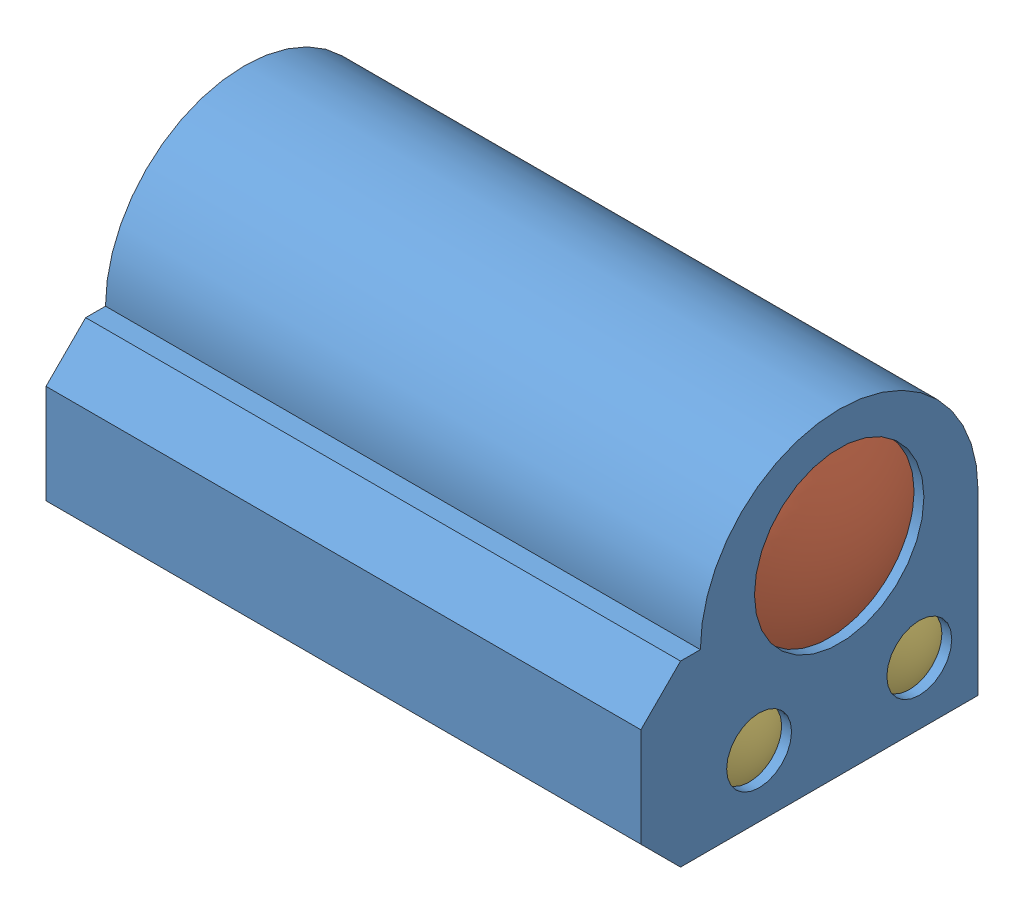
SolidWorks assembly Assem1, configuration Default. Lengths in mm.
Overall size (152.5 80 85).
4 component instances, 3 part files, 6 mates.
Components (placement in the parent):
- cam-1: cam [Default] at (69.598 59.1788 120.9335) size (150 80 85)
- Part2-1: Part2 [Default] at (139.598 109.3315 120.9335) x (1 0 0) z (0 -0.974794 -0.223109) size (7.5 42.74 42.74)
- Part3-1: Part3 [Default] at (139.598 74.7804 141.1326) size (4.5 16.37 16.37)
- Part3-2: Part3 [Default] at (139.598 74.7804 100.7344) size (4.5 16.37 16.37)
Mates (geometry in assembly coordinates):
- Coincident1: coincident anti-aligned: plane of cam-1 through (139.598 109.3315 120.9335) normal (1 0 0); plane of Part2-1 through (139.598 109.3315 120.9335) normal (-1 0 0)
- Concentric1: concentric anti-aligned: cylinder of cam-1 through (139.598 109.3315 120.9335) axis (1 0 0) radius 21.3683; cylinder of Part2-1 through (142.098 109.3315 120.9335) axis (-1 0 0) radius 21.37
- Coincident2: coincident anti-aligned: plane of cam-1 through (139.598 74.7804 141.1326) normal (1 0 0); plane of Part3-1 through (139.598 74.7804 141.1326) normal (-1 0 0)
- Concentric2: concentric anti-aligned: cylinder of cam-1 through (139.598 74.7804 141.1326) axis (1 0 0) radius 8.186; cylinder of Part3-1 through (142.098 74.7804 141.1326) axis (-1 0 0) radius 8.185
- Coincident3: coincident anti-aligned: plane of cam-1 through (139.598 74.7804 100.7344) normal (1 0 0); plane of Part3-2 through (139.598 74.7804 100.7344) normal (-1 0 0)
- Concentric3: concentric anti-aligned: cylinder of cam-1 through (139.598 74.7804 100.7344) axis (1 0 0) radius 8.186; cylinder of Part3-2 through (142.098 74.7804 100.7344) axis (-1 0 0) radius 8.185
